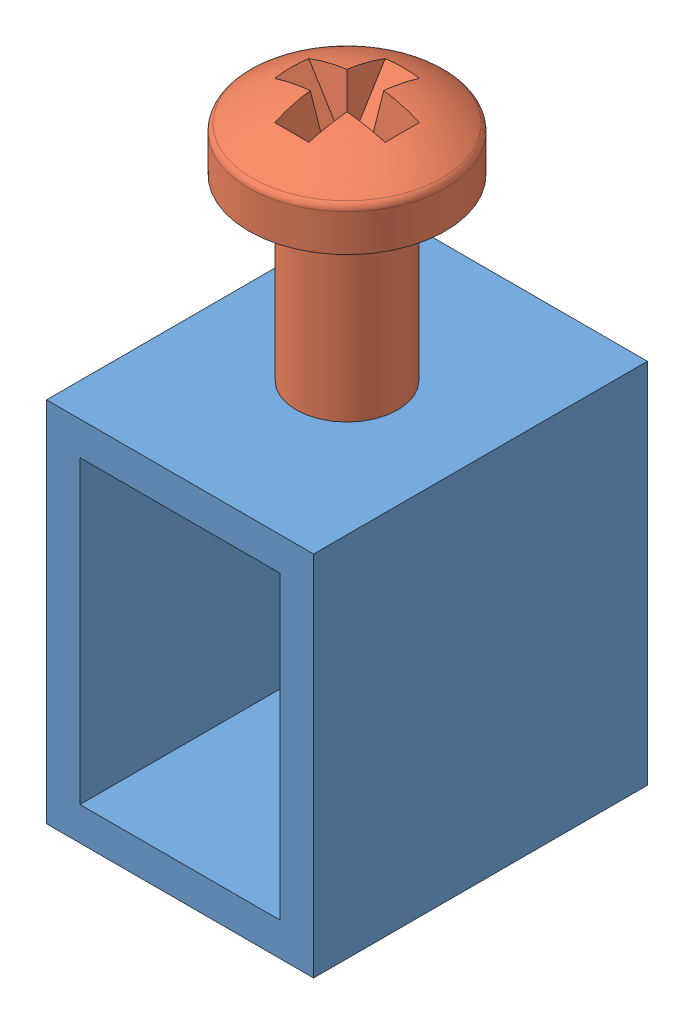
SolidWorks assembly wireholder_with_screw_assembly, configuration Default. Lengths in mm.
Overall size (4 9.26 5).
2 component instances, 2 part files, 2 mates.
Components (placement in the parent):
- wireholder-1: wireholder [Default] at (-75.1268 12.4011 26.568) size (4 5.5 5)
- pan cross head_ai-1: pan cross head_ai [CR-PHMS 0.06-80x0.125x0.125-N] at (-73.6268 21.1937 29.068) x (0 -1 0) z (0 0 1) size (4.26 2.95 2.95)
Mates (geometry in assembly coordinates):
- Concentric1: concentric aligned: cylinder of wireholder-1 through (-73.6268 11.9001 29.068) axis (0 1 0) radius 0.75; cylinder of pan cross head_ai-1 through (-73.6268 46.5937 29.068) axis (0 1 0) radius 1.4732
- Coincident2: coincident aligned: plane of wireholder-1 through (-75.1268 16.9011 31.568) normal (0 -1 0); plane of pan cross head_ai-1 through (-72.8648 16.9011 29.068) normal (0 -1 0)
